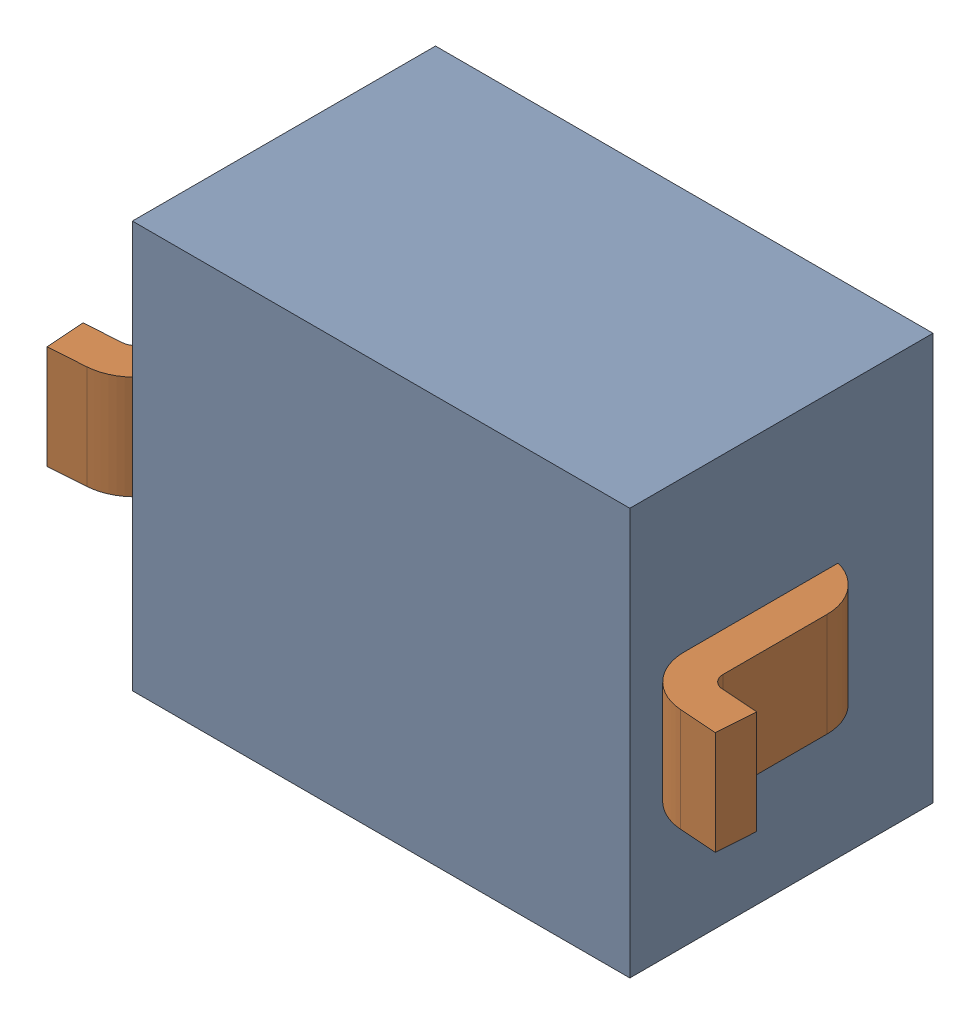
SolidWorks assembly D2, configuration Default. Lengths in mm.
Overall size (2.6 1.57 1.17).
3 component instances, 2 part files, 0 mates.
Components (placement in the parent):
- 1737248736-1: 1737248736 [Default] at (10.15 19.025 -2.814) size (1.92 1.57 1.17)
  - Extruded-39-1: Extruded-39 [Default] at origin size (1.92 1.57 1.17)
- SOD323-1: SOD323 [Default] at (10.1501 19.0249 -1.644) x (-1 0 0) z (0 0 -1) size (2.6 1.35 1.1)
